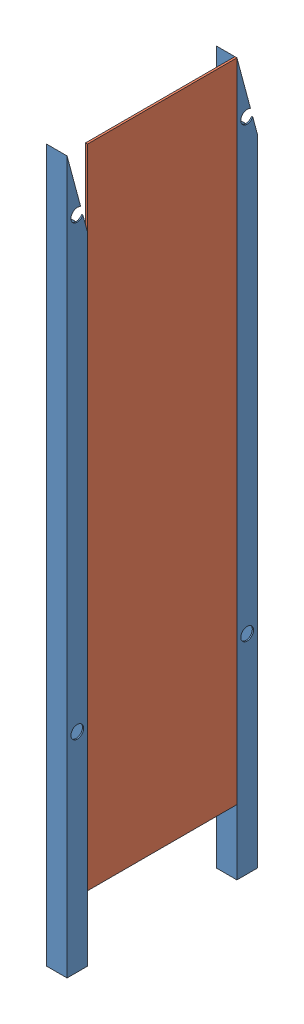
SolidWorks assembly tall_shoot_assembly, configuration Default. Lengths in mm.
Overall size (25.4 826.01 236.22).
3 component instances, 2 part files, 0 mates.
Components (placement in the parent):
- belt_wall_supports-1: belt_wall_supports [Default] at (388.7108 207.1324 994.3626) size (25.4 826.01 25.4)
- belt_wall_supports-3: belt_wall_supports [Default] at (388.7108 207.1324 1205.1826) size (25.4 826.01 25.4)
- polycarb_walls-1: polycarb_walls [Default] at (352.2157 370.6929 1059.8348) x (0 0 1) z (0 1 0) size (185.42 2.54 802.64)
